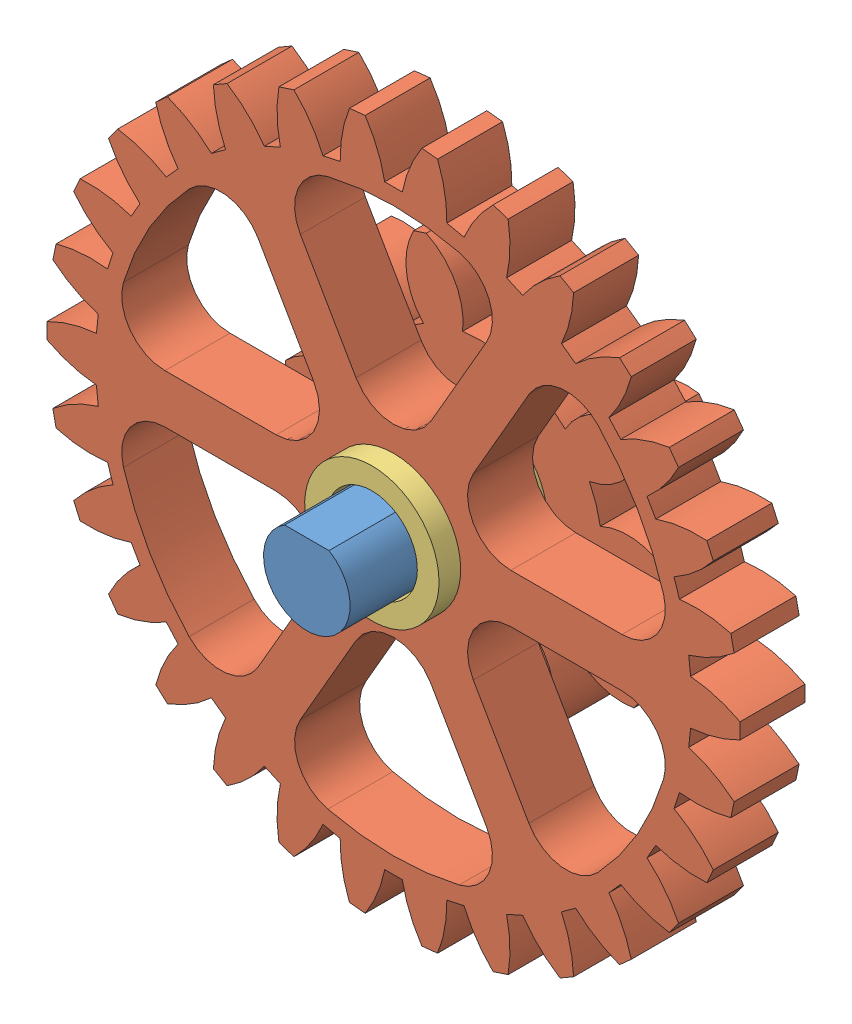
SolidWorks assembly assem_2, configuration Default. Lengths in mm.
Overall size (32 31.89 15).
6 component instances, 3 part files, 12 mates.
Components (placement in the parent):
- axle-1: axle [15mm] at (6.9674 8.0145 3.2605) size (4 3.72 15)
- root_gear-1: root_gear [30T 1.0Mod] at (6.9674 8.0145 11.2605) size (32 31.89 3)
- root_gear-2: root_gear [10T 1.5Mod] at (6.9674 8.0145 7.2605) size (18 17.3 3)
- spacer-1: spacer [4.2mm ID 1L] at (6.9674 8.0145 6.2605) size (6.2 6.2 1)
- spacer-2: spacer [4.2mm ID 1L] at (6.9674 8.0145 14.2605) x (0.300873 0.953664 0) z (0 0 1) size (6.2 6.2 1)
- spacer-3: spacer [4.2mm ID 1L] at (6.9674 8.0145 10.2605) x (0.999497 0.031723 0) z (0 0 1) size (6.2 6.2 1)
Mates (geometry in assembly coordinates):
- Concentric2: concentric aligned: cylinder of axle-1 through (6.9674 8.0145 18.2605) axis (0 0 -1) radius 2; cylinder of spacer-3 through (6.9674 8.0145 11.2605) axis (0 0 -1) radius 2.1
- Concentric9: concentric aligned: cylinder of axle-1 through (6.9674 8.0145 18.2605) axis (0 0 -1) radius 2; cylinder of root_gear-1 through (6.9674 8.0145 14.2605) axis (0 0 -1) radius 2
- Parallel6: parallel anti-aligned: plane of axle-1 through (5.9448 9.7332 18.2605) normal (0 1 0); plane of root_gear-1 through (8.2903 9.5145 14.2605) normal (0 -1 0)
- Concentric10: concentric aligned: cylinder of axle-1 through (6.9674 8.0145 18.2605) axis (0 0 -1) radius 2; cylinder of root_gear-2 through (6.9674 8.0145 10.2605) axis (0 0 -1) radius 2
- Parallel7: parallel anti-aligned: plane of axle-1 through (5.9448 9.7332 18.2605) normal (0 1 0); plane of root_gear-2 through (8.2903 9.5145 10.2605) normal (0 -1 0)
- Concentric11: concentric aligned: cylinder of axle-1 through (6.9674 8.0145 18.2605) axis (0 0 -1) radius 2; cylinder of spacer-2 through (6.9674 8.0145 15.2605) axis (0 0 -1) radius 2.1
- Concentric12: concentric aligned: cylinder of axle-1 through (6.9674 8.0145 18.2605) axis (0 0 -1) radius 2; cylinder of spacer-1 through (6.9674 8.0145 7.2605) axis (0 0 -1) radius 2.1
- Coincident4: coincident anti-aligned: plane of root_gear-2 through (6.9674 8.0145 7.2605) normal (0 0 -1); plane of spacer-1 through (6.9674 8.0145 7.2605) normal (0 0 1)
- Coincident6: coincident anti-aligned: plane of root_gear-2 through (6.9674 8.0145 10.2605) normal (0 0 1); plane of spacer-3 through (6.9674 8.0145 10.2605) normal (0 0 -1)
- Coincident7: coincident anti-aligned: plane of root_gear-1 through (6.9674 8.0145 11.2605) normal (0 0 -1); plane of spacer-3 through (6.9674 8.0145 11.2605) normal (0 0 1)
- Coincident8: coincident aligned: plane of root_gear-1 through (6.9674 8.0145 14.2605) normal (0 0 1); circle of spacer-2
- Distance1: distance = 3 mm aligned: plane of spacer-2 through (6.9674 8.0145 15.2605) normal (0 0 1); plane of axle-1 through (6.9674 8.0145 18.2605) normal (0 0 1)
